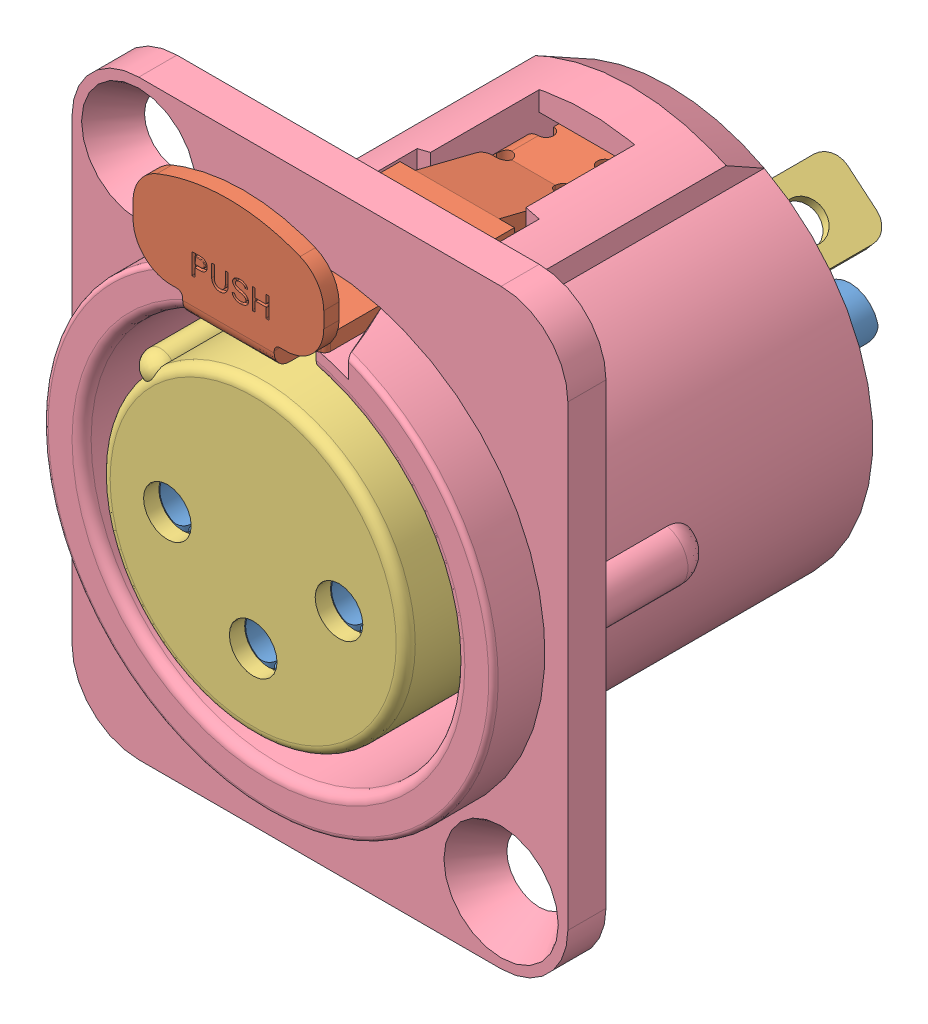
SolidWorks assembly XLR, configuration Default. Lengths in mm.
Overall size (26 32.62 28.11).
8 component instances, 4 part files, 0 mates.
Components (placement in the parent):
- _U10-1: _U10 [Default] at (0 0 -7.75) x (-1 0 0) z (0 0 -1) size (26 32.62 28.11)
  - female-1: female [Default] at (0 4.0575 -0.5) size (18 26.12 28.11)
    - pin ž-1: pin ž [Default] at (4.4999 -4.0574 1.05) x (-1 0 0) z (0 0 -1) size (3 3 26)
    - pin ž-2: pin ž [Default] at (-4.4999 -4.0574 1.05) x (-1 0 0) z (0 0 -1) size (3 3 26)
    - pin ž-3: pin ž [Default] at (0 -8.0073 1.05) x (-1 0 0) z (0 0 -1) size (3 3 26)
    - PUSH šnaper-1: PUSH šnaper [Default] at (0 7.6575 -3.05) size (10 10.8 22.01)
    - female-1: female [Default] at origin size (18 18.35 26.91)
  - _U10-1: _U10 [Default] at origin size (26 31 21.03)
